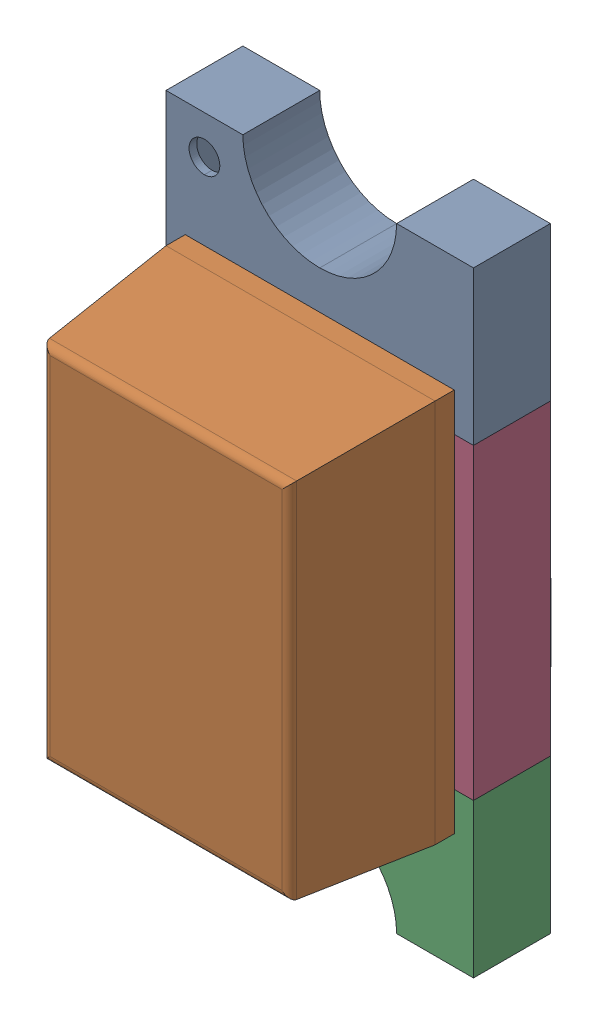
SolidWorks assembly LED1, configuration Défaut. Lengths in mm.
Overall size (0.8 1.6 0.6).
6 component instances, 5 part files, 0 mates.
Components (placement in the parent):
- User Library-LED_0603_R-1: User Library-LED_0603_R [Défaut] at (75.6666 -43.8786 0) x (0 -1 0) z (0 0 1) size (1.6 0.8 0.6)
  - User Library-LED_0603_R_Pocket002-1: User Library-LED_0603_R_Pocket002 [Défaut] at origin size (0.4 0.8 0.2)
  - User Library-LED_0603_R_Pad004-1: User Library-LED_0603_R_Pad004 [Défaut] x (1 0 0) z (0 0 -1) size (0.4 0.8 0)
  - User Library-LED_0603_R_Fillet-1: User Library-LED_0603_R_Fillet [Défaut] at origin size (1 0.7 0.4)
  - User Library-LED_0603_R_Pocket001-1: User Library-LED_0603_R_Pocket001 [Défaut] at origin size (0.4 0.8 0.2)
  - User Library-LED_0603_R_Pad-1: User Library-LED_0603_R_Pad [Défaut] at origin size (0.8 0.8 0.2)
